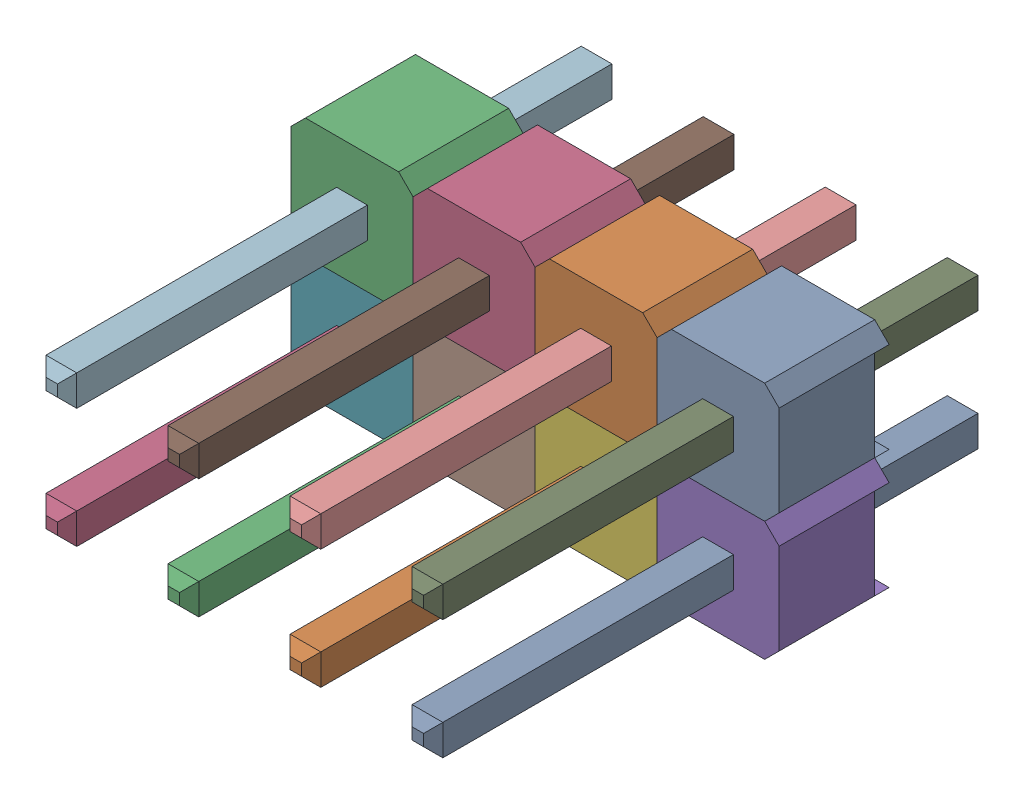
SolidWorks assembly User Library-2.54mm Male Header (4x2), configuration ﾃﾞﾌｫﾙﾄ. Lengths in mm.
Overall size (10.16 4.98 11.54).
6 component instances, 2 part files, 0 mates.
Components (placement in the parent):
- User Library-Header_Male_4Pin-1: User Library-Header_Male_4Pin [ﾃﾞﾌｫﾙﾄ] at (-35.6012 -1.8987 15.2958) size (10.16 2.49 11.54)
  - User Library-Header_Male_4Pin_PinArray-1: User Library-Header_Male_4Pin_PinArray [ﾃﾞﾌｫﾙﾄ] at origin size (8.26 0.64 11.54)
  - User Library-Header_Male_4Pin_BodyArray-1: User Library-Header_Male_4Pin_BodyArray [ﾃﾞﾌｫﾙﾄ] at origin size (10.16 2.49 2.29)
- User Library-Header_Male_4Pin-1-1: User Library-Header_Male_4Pin-1 [ﾃﾞﾌｫﾙﾄ] at (-35.6012 0.5913 15.2958) size (10.16 2.49 11.54)
  - User Library-Header_Male_4Pin_PinArray-1: User Library-Header_Male_4Pin_PinArray [ﾃﾞﾌｫﾙﾄ] at origin size (8.26 0.64 11.54)
  - User Library-Header_Male_4Pin_BodyArray-1: User Library-Header_Male_4Pin_BodyArray [ﾃﾞﾌｫﾙﾄ] at origin size (10.16 2.49 2.29)
